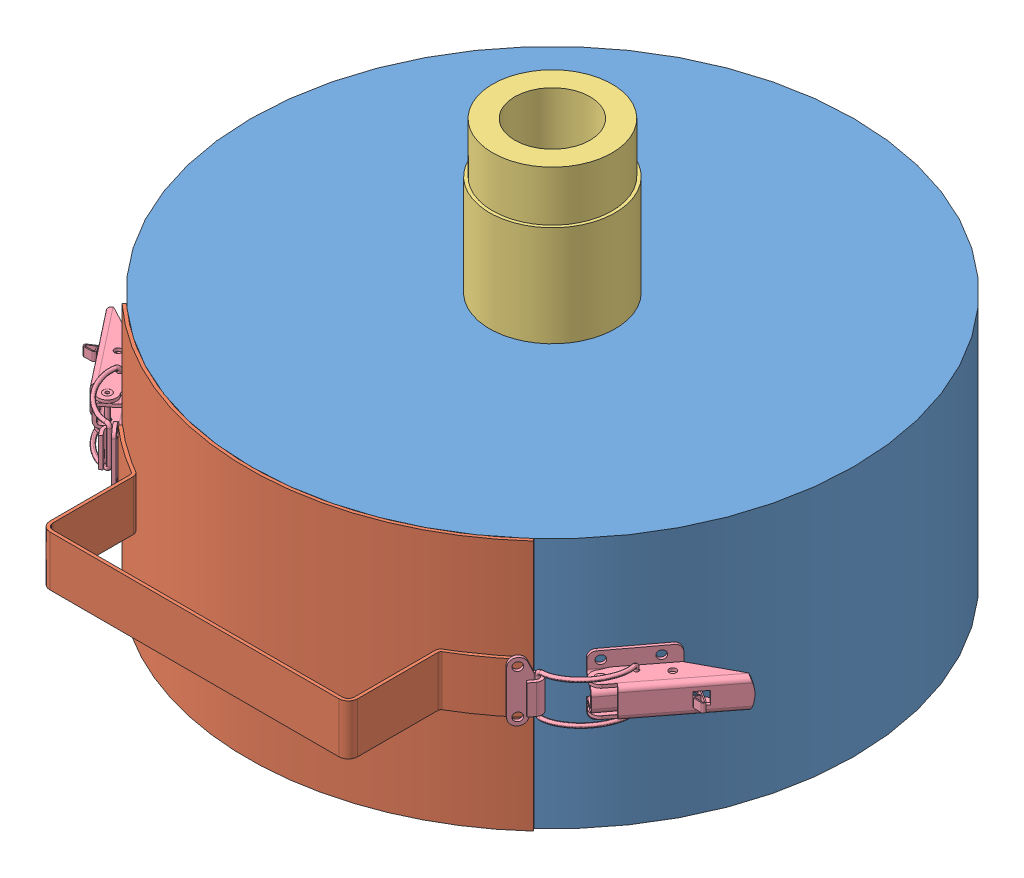
SolidWorks assembly Filter Assembly, configuration Default. Lengths in mm.
Overall size (336.71 203.2 333.38).
5 component instances, 4 part files, 13 mates.
Components (placement in the parent):
- Filter Case-1: Filter Case [Default] at origin size (304.8 127 304.8)
- Filter Cover Plate-1: Filter Cover Plate [Default] x (-1 0 0) z (0 0 -1) size (208.06 127 68.61)
- Threaded Adaper - 2in-2: Threaded Adaper - 2in [Default] at (0 63.5 0) size (63.5 76.2 63.5)
- Filter Screen Latches - 1889A430-1: Filter Screen Latches - 1889A430 [Default] at (116.2139 0 99.0468) x (0 -1 0) z (-0.600065 0 0.799951) size (30 20.98 87.72)
- Filter Screen Latches - 1889A430-2: Filter Screen Latches - 1889A430 [Default] at (-116.1817 0 98.9703) x (0 1 0) z (0.606538 0 0.795055) size (30 20.98 87.72)
Mates (geometry in assembly coordinates):
- Coincident1: coincident anti-aligned: plane of Filter Cover Plate-1 through (0 0 0) normal (-1 0 0); plane of assembly through (0 0 0) normal (1 0 0)
- Concentric1: concentric aligned: cylinder of Filter Case-1 through (0 63.5 0) axis (0 -1 0) radius 152.4; cylinder of Filter Cover Plate-1 through (0 63.5 0) axis (0 -1 0) radius 152.4
- Coincident2: coincident aligned: plane of Filter Case-1 through (0 63.5 0) normal (0 1 0); plane of Filter Cover Plate-1 through (0 63.5 0) normal (0 1 0)
- Coincident3: coincident anti-aligned: plane of Filter Case-1 through (0 63.5 0) normal (0 1 0); plane of Threaded Adaper - 2in-2 through (0 63.5 0) normal (0 -1 0)
- Concentric2: concentric aligned: cylinder of Filter Case-1 through (0 63.5 0) axis (0 -1 0) radius 152.4; cylinder of Threaded Adaper - 2in-2 through (0 139.7 0) axis (0 -1 0) radius 31.75
- Parallel1: parallel: line of Filter Cover Plate-1 through (104.0324 63.5 113.5315) axis (0 -1 0); plane of Filter Screen Latches - 1889A430-1 through (116.2139 0 99.0468) normal (-0.600065 0 0.799951)
- Tangent2: tangent anti-aligned: cylinder of Filter Case-1 through (0 63.5 0) axis (0 -1 0) radius 152.4; plane of Filter Screen Latches - 1889A430-1 through (116.2139 -14.9987 99.0468) normal (-0.799951 0 -0.600065)
- Coincident5: coincident anti-aligned: plane of Filter Screen Latches - 1889A430-1; plane of assembly through (0 0 0) normal (0 1 0)
- Coincident6: coincident: plane of Filter Cover Plate-1 through (104.0324 63.5 113.5315) normal (0.737277 0 -0.67559); line of Filter Screen Latches - 1889A430-1 through (104.7561 7.5 114.3213) axis (0 -1 0)
- Parallel2: parallel aligned: line of Filter Cover Plate-1 through (-104.0324 63.5 113.5315) axis (0 -1 0); plane of Filter Screen Latches - 1889A430-2 through (-116.1817 0 98.9703) normal (0.606538 0 0.795055)
- Tangent3: tangent anti-aligned: cylinder of Filter Case-1 through (0 63.5 0) axis (0 -1 0) radius 152.4; plane of Filter Screen Latches - 1889A430-2 through (-116.1817 14.9987 98.9703) normal (0.795055 0 -0.606538)
- Coincident7: coincident aligned: plane of Filter Screen Latches - 1889A430-2; plane of assembly through (0 0 0) normal (0 1 0)
- Coincident8: coincident: plane of Filter Cover Plate-1 through (-104.0324 63.5 113.5315) normal (-0.737277 0 -0.67559); line of Filter Screen Latches - 1889A430-2 through (-104.6003 -7.5 114.1512) axis (0 1 0)
